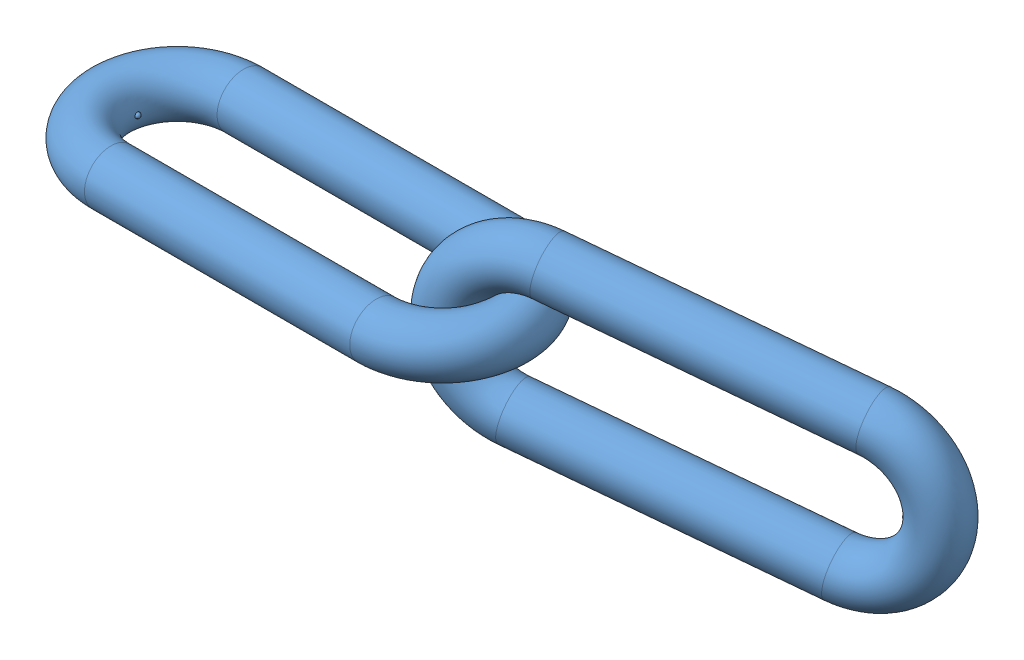
SolidWorks assembly Chain, configuration Default. Lengths in mm.
Overall size (29.96 10.07 9.12).
2 component instances, 1 part files, 1 mates.
Components (placement in the parent):
- ChanLink-1: ChanLink [Default] at (-15.554 12.9589 -3.2349) size (17 2 7)
- ChanLink-2: ChanLink [Default] at (-2.644 12.6851 -3.6674) x (0.939977 -0.182582 -0.288283) z (-0.161098 -0.982182 0.09678) size (17 2 7)
Mates (geometry in assembly coordinates):
- Concentric1: concentric: sphere of ChanLink-1; sphere of ChanLink-2
